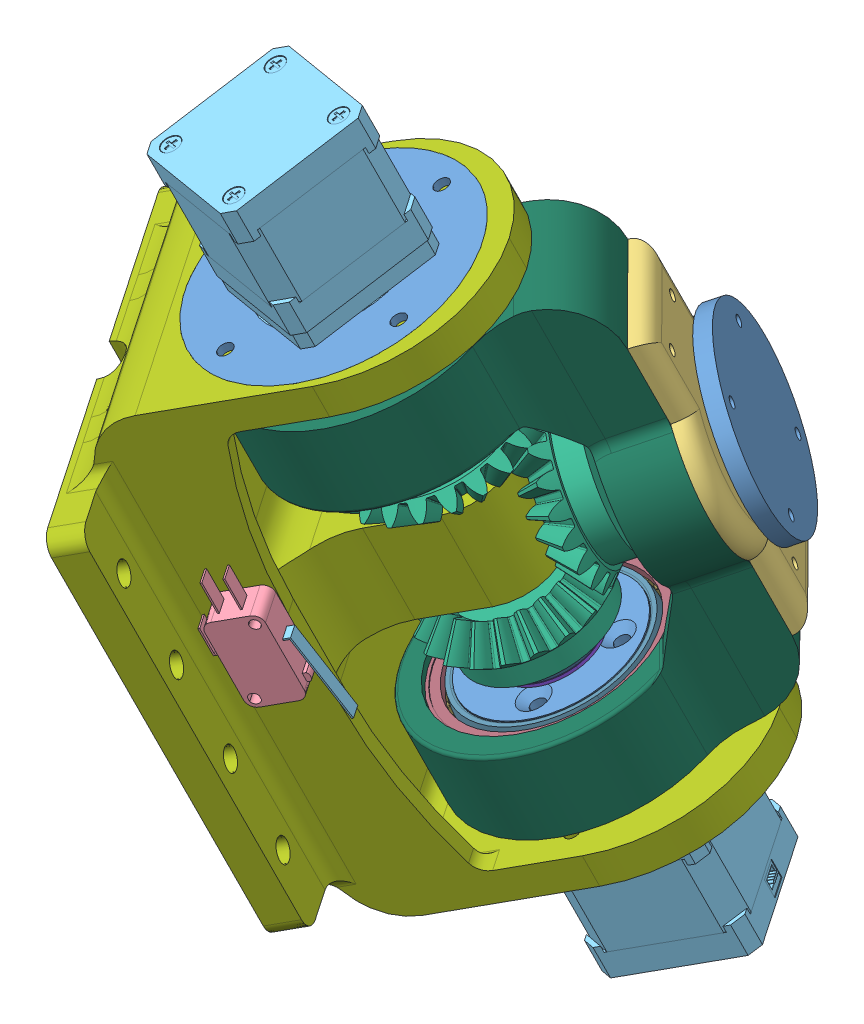
SolidWorks assembly UOM20-4A004, configuration Default. Lengths in mm.
Overall size (196.11 254.11 206.09).
236 component instances, 25 part files, 61 mates.
Components (placement in the parent):
- Motor sleeve-1: Motor sleeve [Default] at (155.4938 95.549 -26.0395) x (0.240387 -0.911388 -0.334046) z (0.948422 0.147261 0.280731) size (40 78 78)
- Motor sleeve-2: Motor sleeve [Default] at (194.9173 -53.9186 -80.823) x (-0.240387 0.911388 0.334046) z (-0.822054 -0.374149 0.429231) size (40 78 78)
- HK_1412-1: HK_1412 [Default] at (171.5998 34.486 -48.4206) x (0.240387 -0.911388 -0.334046) z (0.778305 -0.024672 0.627401) size (12 20 20)
  - HK_1412_3-1: HK_1412_3 [Default] x (1 0 0) z (0 -0.382683 0.92388) size (7.3 2 2)
  - HK_1412_3-2: HK_1412_3 [Default] x (1 0 0) z (0 -0.707107 0.707107) size (7.3 2 2)
  - HK_1412_3-3: HK_1412_3 [Default] x (1 0 0) z (0 -0.92388 0.382683) size (7.3 2 2)
  - HK_1412_3-4: HK_1412_3 [Default] x (1 0 0) z (0 -1 0) size (7.3 2 2)
  - HK_1412_3-5: HK_1412_3 [Default] x (1 0 0) z (0 -0.92388 -0.382683) size (7.3 2 2)
  - HK_1412_3-6: HK_1412_3 [Default] x (1 0 0) z (0 -0.707107 -0.707107) size (7.3 2 2)
  - HK_1412_3-7: HK_1412_3 [Default] x (1 0 0) z (0 -0.382683 -0.92388) size (7.3 2 2)
  - HK_1412_3-8: HK_1412_3 [Default] x (1 0 0) z (0 0 -1) size (7.3 2 2)
  - HK_1412_3-9: HK_1412_3 [Default] x (1 0 0) z (0 0.382683 -0.92388) size (7.3 2 2)
  - HK_1412_3-10: HK_1412_3 [Default] x (1 0 0) z (0 0.707107 -0.707107) size (7.3 2 2)
  - HK_1412_3-11: HK_1412_3 [Default] x (1 0 0) z (0 0.92388 -0.382683) size (7.3 2 2)
  - HK_1412_3-12: HK_1412_3 [Default] x (1 0 0) z (0 1 0) size (7.3 2 2)
  - HK_1412_3-13: HK_1412_3 [Default] x (1 0 0) z (0 0.92388 0.382683) size (7.3 2 2)
  - HK_1412_3-14: HK_1412_3 [Default] x (1 0 0) z (0 0.707107 0.707107) size (7.3 2 2)
  - HK_1412_3-15: HK_1412_3 [Default] x (1 0 0) z (0 0.382683 0.92388) size (7.3 2 2)
  - HK_1412_3-16: HK_1412_3 [Default] at origin size (7.3 2 2)
  - HK_1412_20-1: HK_1412_20 [Default] x (1 0 0) z (0 -0.382683 0.92388) size (7.3 2 2)
  - HK_1412_20-2: HK_1412_20 [Default] x (1 0 0) z (0 -0.707107 0.707107) size (7.3 2 2)
  - HK_1412_20-3: HK_1412_20 [Default] x (1 0 0) z (0 -0.92388 0.382683) size (7.3 2 2)
  - HK_1412_20-4: HK_1412_20 [Default] x (1 0 0) z (0 -1 0) size (7.3 2 2)
  - HK_1412_20-5: HK_1412_20 [Default] x (1 0 0) z (0 -0.92388 -0.382683) size (7.3 2 2)
  - HK_1412_20-6: HK_1412_20 [Default] x (1 0 0) z (0 -0.707107 -0.707107) size (7.3 2 2)
  - HK_1412_20-7: HK_1412_20 [Default] x (1 0 0) z (0 -0.382683 -0.92388) size (7.3 2 2)
  - HK_1412_20-8: HK_1412_20 [Default] x (1 0 0) z (0 0 -1) size (7.3 2 2)
  - HK_1412_20-9: HK_1412_20 [Default] x (1 0 0) z (0 0.382683 -0.92388) size (7.3 2 2)
  - HK_1412_20-10: HK_1412_20 [Default] x (1 0 0) z (0 0.707107 -0.707107) size (7.3 2 2)
  - HK_1412_20-11: HK_1412_20 [Default] x (1 0 0) z (0 0.92388 -0.382683) size (7.3 2 2)
  - HK_1412_20-12: HK_1412_20 [Default] x (1 0 0) z (0 1 0) size (7.3 2 2)
  - HK_1412_20-13: HK_1412_20 [Default] x (1 0 0) z (0 0.92388 0.382683) size (7.3 2 2)
  - HK_1412_20-14: HK_1412_20 [Default] x (1 0 0) z (0 0.707107 0.707107) size (7.3 2 2)
  - HK_1412_20-15: HK_1412_20 [Default] x (1 0 0) z (0 0.382683 0.92388) size (7.3 2 2)
  - HK_1412_20-16: HK_1412_20 [Default] at origin size (7.3 2 2)
  - HK_1412_37-1: HK_1412_37 [Default] at origin size (12 20 20)
- HK_1412-2: HK_1412 [Default] at (175.9267 18.081 -54.4334) x (0.240387 -0.911388 -0.334046) z (0.468046 0.410319 -0.782669) size (12 20 20)
  - HK_1412_3-1: HK_1412_3 [Default] x (1 0 0) z (0 -0.382683 0.92388) size (7.3 2 2)
  - HK_1412_3-2: HK_1412_3 [Default] x (1 0 0) z (0 -0.707107 0.707107) size (7.3 2 2)
  - HK_1412_3-3: HK_1412_3 [Default] x (1 0 0) z (0 -0.92388 0.382683) size (7.3 2 2)
  - HK_1412_3-4: HK_1412_3 [Default] x (1 0 0) z (0 -1 0) size (7.3 2 2)
  - HK_1412_3-5: HK_1412_3 [Default] x (1 0 0) z (0 -0.92388 -0.382683) size (7.3 2 2)
  - HK_1412_3-6: HK_1412_3 [Default] x (1 0 0) z (0 -0.707107 -0.707107) size (7.3 2 2)
  - HK_1412_3-7: HK_1412_3 [Default] x (1 0 0) z (0 -0.382683 -0.92388) size (7.3 2 2)
  - HK_1412_3-8: HK_1412_3 [Default] x (1 0 0) z (0 0 -1) size (7.3 2 2)
  - HK_1412_3-9: HK_1412_3 [Default] x (1 0 0) z (0 0.382683 -0.92388) size (7.3 2 2)
  - HK_1412_3-10: HK_1412_3 [Default] x (1 0 0) z (0 0.707107 -0.707107) size (7.3 2 2)
  - HK_1412_3-11: HK_1412_3 [Default] x (1 0 0) z (0 0.92388 -0.382683) size (7.3 2 2)
  - HK_1412_3-12: HK_1412_3 [Default] x (1 0 0) z (0 1 0) size (7.3 2 2)
  - HK_1412_3-13: HK_1412_3 [Default] x (1 0 0) z (0 0.92388 0.382683) size (7.3 2 2)
  - HK_1412_3-14: HK_1412_3 [Default] x (1 0 0) z (0 0.707107 0.707107) size (7.3 2 2)
  - HK_1412_3-15: HK_1412_3 [Default] x (1 0 0) z (0 0.382683 0.92388) size (7.3 2 2)
  - HK_1412_3-16: HK_1412_3 [Default] at origin size (7.3 2 2)
  - HK_1412_20-1: HK_1412_20 [Default] x (1 0 0) z (0 -0.382683 0.92388) size (7.3 2 2)
  - HK_1412_20-2: HK_1412_20 [Default] x (1 0 0) z (0 -0.707107 0.707107) size (7.3 2 2)
  - HK_1412_20-3: HK_1412_20 [Default] x (1 0 0) z (0 -0.92388 0.382683) size (7.3 2 2)
  - HK_1412_20-4: HK_1412_20 [Default] x (1 0 0) z (0 -1 0) size (7.3 2 2)
  - HK_1412_20-5: HK_1412_20 [Default] x (1 0 0) z (0 -0.92388 -0.382683) size (7.3 2 2)
  - HK_1412_20-6: HK_1412_20 [Default] x (1 0 0) z (0 -0.707107 -0.707107) size (7.3 2 2)
  - HK_1412_20-7: HK_1412_20 [Default] x (1 0 0) z (0 -0.382683 -0.92388) size (7.3 2 2)
  - HK_1412_20-8: HK_1412_20 [Default] x (1 0 0) z (0 0 -1) size (7.3 2 2)
  - HK_1412_20-9: HK_1412_20 [Default] x (1 0 0) z (0 0.382683 -0.92388) size (7.3 2 2)
  - HK_1412_20-10: HK_1412_20 [Default] x (1 0 0) z (0 0.707107 -0.707107) size (7.3 2 2)
  - HK_1412_20-11: HK_1412_20 [Default] x (1 0 0) z (0 0.92388 -0.382683) size (7.3 2 2)
  - HK_1412_20-12: HK_1412_20 [Default] x (1 0 0) z (0 1 0) size (7.3 2 2)
  - HK_1412_20-13: HK_1412_20 [Default] x (1 0 0) z (0 0.92388 0.382683) size (7.3 2 2)
  - HK_1412_20-14: HK_1412_20 [Default] x (1 0 0) z (0 0.707107 0.707107) size (7.3 2 2)
  - HK_1412_20-15: HK_1412_20 [Default] x (1 0 0) z (0 0.382683 0.92388) size (7.3 2 2)
  - HK_1412_20-16: HK_1412_20 [Default] at origin size (7.3 2 2)
  - HK_1412_37-1: HK_1412_37 [Default] at origin size (12 20 20)
- 17HS15-1684D-HG10-AR3-2: 17HS15-1684D-HG10-AR3 [Default] at (196.1193 -58.4755 -82.4933) x (0.822054 0.374149 -0.429231) z (-0.240387 0.911388 0.334046) size (42.88 42 103.5)
- 17HS15-1684D-HG10-AR3-3: 17HS15-1684D-HG10-AR3 [Default] at (154.2919 100.1059 -24.3693) x (-0.948422 -0.147261 -0.280731) z (0.240387 -0.911388 -0.334046) size (42.88 42 103.5)
- shaft-1: shaft [Default] at (185.6624 -18.8302 -67.9623) x (-0.240387 0.911388 0.334046) z (-0.716686 0.065452 -0.694318) size (42 17 17)
- shaft-2: shaft [Default] at (164.7487 60.4605 -38.9003) x (0.240387 -0.911388 -0.334046) z (-0.880225 -0.059609 -0.470799) size (42 17 17)
- AXK_1528___AS_1528___AS_1528-2: AXK_1528___AS_1528___AS_1528 [Default] at (165.5901 57.2707 -40.0694) x (0.240387 -0.911388 -0.334046) z (0.891346 0.343519 -0.295799) size (4 28 28)
  - AXK_1528___AS_1528___AS_1528_3-1: AXK_1528___AS_1528___AS_1528_3 [Default] x (1 0 0) z (0 -0.309017 0.951057) size (2 5 2)
  - AXK_1528___AS_1528___AS_1528_3-2: AXK_1528___AS_1528___AS_1528_3 [Default] x (1 0 0) z (0 -0.587785 0.809017) size (2 5 2)
  - AXK_1528___AS_1528___AS_1528_3-3: AXK_1528___AS_1528___AS_1528_3 [Default] x (1 0 0) z (0 -0.809017 0.587785) size (2 5 2)
  - AXK_1528___AS_1528___AS_1528_3-4: AXK_1528___AS_1528___AS_1528_3 [Default] x (1 0 0) z (0 -0.951057 0.309017) size (2 5 2)
  - AXK_1528___AS_1528___AS_1528_3-5: AXK_1528___AS_1528___AS_1528_3 [Default] x (1 0 0) z (0 -1 0) size (2 5 2)
  - AXK_1528___AS_1528___AS_1528_3-6: AXK_1528___AS_1528___AS_1528_3 [Default] x (1 0 0) z (0 -0.951057 -0.309017) size (2 5 2)
  - AXK_1528___AS_1528___AS_1528_3-7: AXK_1528___AS_1528___AS_1528_3 [Default] x (1 0 0) z (0 -0.809017 -0.587785) size (2 5 2)
  - AXK_1528___AS_1528___AS_1528_3-8: AXK_1528___AS_1528___AS_1528_3 [Default] x (1 0 0) z (0 -0.587785 -0.809017) size (2 5 2)
  - AXK_1528___AS_1528___AS_1528_3-9: AXK_1528___AS_1528___AS_1528_3 [Default] x (1 0 0) z (0 -0.309017 -0.951057) size (2 5 2)
  - AXK_1528___AS_1528___AS_1528_3-10: AXK_1528___AS_1528___AS_1528_3 [Default] x (1 0 0) z (0 0 -1) size (2 5 2)
  - AXK_1528___AS_1528___AS_1528_3-11: AXK_1528___AS_1528___AS_1528_3 [Default] x (1 0 0) z (0 0.309017 -0.951057) size (2 5 2)
  - AXK_1528___AS_1528___AS_1528_3-12: AXK_1528___AS_1528___AS_1528_3 [Default] x (1 0 0) z (0 0.587785 -0.809017) size (2 5 2)
  - AXK_1528___AS_1528___AS_1528_3-13: AXK_1528___AS_1528___AS_1528_3 [Default] x (1 0 0) z (0 0.809017 -0.587785) size (2 5 2)
  - AXK_1528___AS_1528___AS_1528_3-14: AXK_1528___AS_1528___AS_1528_3 [Default] x (1 0 0) z (0 0.951057 -0.309017) size (2 5 2)
  - AXK_1528___AS_1528___AS_1528_3-15: AXK_1528___AS_1528___AS_1528_3 [Default] x (1 0 0) z (0 1 0) size (2 5 2)
  - AXK_1528___AS_1528___AS_1528_3-16: AXK_1528___AS_1528___AS_1528_3 [Default] x (1 0 0) z (0 0.951057 0.309017) size (2 5 2)
  - AXK_1528___AS_1528___AS_1528_3-17: AXK_1528___AS_1528___AS_1528_3 [Default] x (1 0 0) z (0 0.809017 0.587785) size (2 5 2)
  - AXK_1528___AS_1528___AS_1528_3-18: AXK_1528___AS_1528___AS_1528_3 [Default] x (1 0 0) z (0 0.587785 0.809017) size (2 5 2)
  - AXK_1528___AS_1528___AS_1528_3-19: AXK_1528___AS_1528___AS_1528_3 [Default] x (1 0 0) z (0 0.309017 0.951057) size (2 5 2)
  - AXK_1528___AS_1528___AS_1528_3-20: AXK_1528___AS_1528___AS_1528_3 [Default] at origin size (2 5 2)
  - AXK_1528___AS_1528___AS_1528_24-1: AXK_1528___AS_1528___AS_1528_24 [Default] at origin size (1 28 28)
  - AXK_1528___AS_1528___AS_1528_26-1: AXK_1528___AS_1528___AS_1528_26 [Default] at origin size (1 28 28)
  - AXK_1528___AS_1528___AS_1528_28-1: AXK_1528___AS_1528___AS_1528_28 [Default] at origin size (1.6 28 28)
- 2mm spacer-1: 2mm spacer [Default] at (166.792 52.7138 -41.7397) x (0.953181 0.156591 0.258701) z (-0.240387 0.911388 0.334046) size (28 28 1.5)
- AXK_1528___AS_1528___AS_1528-3: AXK_1528___AS_1528___AS_1528 [Default] at (184.8211 -15.6403 -66.7931) x (0.240387 -0.911388 -0.334046) z (0.94161 0.135359 0.3083) size (4 28 28)
  - AXK_1528___AS_1528___AS_1528_3-1: AXK_1528___AS_1528___AS_1528_3 [Default] x (1 0 0) z (0 -0.309017 0.951057) size (2 5 2)
  - AXK_1528___AS_1528___AS_1528_3-2: AXK_1528___AS_1528___AS_1528_3 [Default] x (1 0 0) z (0 -0.587785 0.809017) size (2 5 2)
  - AXK_1528___AS_1528___AS_1528_3-3: AXK_1528___AS_1528___AS_1528_3 [Default] x (1 0 0) z (0 -0.809017 0.587785) size (2 5 2)
  - AXK_1528___AS_1528___AS_1528_3-4: AXK_1528___AS_1528___AS_1528_3 [Default] x (1 0 0) z (0 -0.951057 0.309017) size (2 5 2)
  - AXK_1528___AS_1528___AS_1528_3-5: AXK_1528___AS_1528___AS_1528_3 [Default] x (1 0 0) z (0 -1 0) size (2 5 2)
  - AXK_1528___AS_1528___AS_1528_3-6: AXK_1528___AS_1528___AS_1528_3 [Default] x (1 0 0) z (0 -0.951057 -0.309017) size (2 5 2)
  - AXK_1528___AS_1528___AS_1528_3-7: AXK_1528___AS_1528___AS_1528_3 [Default] x (1 0 0) z (0 -0.809017 -0.587785) size (2 5 2)
  - AXK_1528___AS_1528___AS_1528_3-8: AXK_1528___AS_1528___AS_1528_3 [Default] x (1 0 0) z (0 -0.587785 -0.809017) size (2 5 2)
  - AXK_1528___AS_1528___AS_1528_3-9: AXK_1528___AS_1528___AS_1528_3 [Default] x (1 0 0) z (0 -0.309017 -0.951057) size (2 5 2)
  - AXK_1528___AS_1528___AS_1528_3-10: AXK_1528___AS_1528___AS_1528_3 [Default] x (1 0 0) z (0 0 -1) size (2 5 2)
  - AXK_1528___AS_1528___AS_1528_3-11: AXK_1528___AS_1528___AS_1528_3 [Default] x (1 0 0) z (0 0.309017 -0.951057) size (2 5 2)
  - AXK_1528___AS_1528___AS_1528_3-12: AXK_1528___AS_1528___AS_1528_3 [Default] x (1 0 0) z (0 0.587785 -0.809017) size (2 5 2)
  - AXK_1528___AS_1528___AS_1528_3-13: AXK_1528___AS_1528___AS_1528_3 [Default] x (1 0 0) z (0 0.809017 -0.587785) size (2 5 2)
  - AXK_1528___AS_1528___AS_1528_3-14: AXK_1528___AS_1528___AS_1528_3 [Default] x (1 0 0) z (0 0.951057 -0.309017) size (2 5 2)
  - AXK_1528___AS_1528___AS_1528_3-15: AXK_1528___AS_1528___AS_1528_3 [Default] x (1 0 0) z (0 1 0) size (2 5 2)
  - AXK_1528___AS_1528___AS_1528_3-16: AXK_1528___AS_1528___AS_1528_3 [Default] x (1 0 0) z (0 0.951057 0.309017) size (2 5 2)
  - AXK_1528___AS_1528___AS_1528_3-17: AXK_1528___AS_1528___AS_1528_3 [Default] x (1 0 0) z (0 0.809017 0.587785) size (2 5 2)
  - AXK_1528___AS_1528___AS_1528_3-18: AXK_1528___AS_1528___AS_1528_3 [Default] x (1 0 0) z (0 0.587785 0.809017) size (2 5 2)
  - AXK_1528___AS_1528___AS_1528_3-19: AXK_1528___AS_1528___AS_1528_3 [Default] x (1 0 0) z (0 0.309017 0.951057) size (2 5 2)
  - AXK_1528___AS_1528___AS_1528_3-20: AXK_1528___AS_1528___AS_1528_3 [Default] at origin size (2 5 2)
  - AXK_1528___AS_1528___AS_1528_24-1: AXK_1528___AS_1528___AS_1528_24 [Default] at origin size (1 28 28)
  - AXK_1528___AS_1528___AS_1528_26-1: AXK_1528___AS_1528___AS_1528_26 [Default] at origin size (1 28 28)
  - AXK_1528___AS_1528___AS_1528_28-1: AXK_1528___AS_1528___AS_1528_28 [Default] at origin size (1.6 28 28)
- 2mm spacer-2: 2mm spacer [Default] at (183.9797 -12.4505 -65.6239) x (0.94161 0.135359 0.3083) z (-0.240387 0.911388 0.334046) size (28 28 1.5)
- NKI_50_25-1: NKI_50_25 [Default] at (185.3018 -17.4631 -67.4612) x (0.240387 -0.911388 -0.334046) z (0.92532 0.11119 0.36252) size (25 68.42 68)
  - NKI_50_25_37-1: NKI_50_25_37 [Default] x (1 0 0) z (0 -0.189251 0.981929) size (18.8 3.5 3.5)
  - NKI_50_25_37-2: NKI_50_25_37 [Default] x (1 0 0) z (0 -0.371662 0.928368) size (18.8 3.5 3.5)
  - NKI_50_25_37-3: NKI_50_25_37 [Default] x (1 0 0) z (0 -0.540641 0.841254) size (18.8 3.5 3.5)
  - NKI_50_25_37-4: NKI_50_25_37 [Default] x (1 0 0) z (0 -0.690079 0.723734) size (18.8 3.5 3.5)
  - NKI_50_25_37-5: NKI_50_25_37 [Default] x (1 0 0) z (0 -0.814576 0.580057) size (18.8 3.5 3.5)
  - NKI_50_25_37-6: NKI_50_25_37 [Default] x (1 0 0) z (0 -0.909632 0.415415) size (18.8 3.5 3.5)
  - NKI_50_25_37-7: NKI_50_25_37 [Default] x (1 0 0) z (0 -0.971812 0.235759) size (18.8 3.5 3.5)
  - NKI_50_25_37-8: NKI_50_25_37 [Default] x (1 0 0) z (0 -0.998867 0.047582) size (18.8 3.5 3.5)
  - NKI_50_25_37-9: NKI_50_25_37 [Default] x (1 0 0) z (0 -0.989821 -0.142315) size (18.8 3.5 3.5)
  - NKI_50_25_37-10: NKI_50_25_37 [Default] x (1 0 0) z (0 -0.945001 -0.327068) size (18.8 3.5 3.5)
  - NKI_50_25_37-11: NKI_50_25_37 [Default] x (1 0 0) z (0 -0.866025 -0.5) size (18.8 3.5 3.5)
  - NKI_50_25_37-12: NKI_50_25_37 [Default] x (1 0 0) z (0 -0.75575 -0.654861) size (18.8 3.5 3.5)
  - NKI_50_25_37-13: NKI_50_25_37 [Default] x (1 0 0) z (0 -0.618159 -0.786053) size (18.8 3.5 3.5)
  - NKI_50_25_37-14: NKI_50_25_37 [Default] x (1 0 0) z (0 -0.458227 -0.888835) size (18.8 3.5 3.5)
  - NKI_50_25_37-15: NKI_50_25_37 [Default] x (1 0 0) z (0 -0.281733 -0.959493) size (18.8 3.5 3.5)
  - NKI_50_25_37-16: NKI_50_25_37 [Default] x (1 0 0) z (0 -0.095056 -0.995472) size (18.8 3.5 3.5)
  - NKI_50_25_37-17: NKI_50_25_37 [Default] x (1 0 0) z (0 0.095056 -0.995472) size (18.8 3.5 3.5)
  - NKI_50_25_37-18: NKI_50_25_37 [Default] x (1 0 0) z (0 0.281733 -0.959493) size (18.8 3.5 3.5)
  - NKI_50_25_37-19: NKI_50_25_37 [Default] x (1 0 0) z (0 0.458227 -0.888835) size (18.8 3.5 3.5)
  - NKI_50_25_37-20: NKI_50_25_37 [Default] x (1 0 0) z (0 0.618159 -0.786053) size (18.8 3.5 3.5)
  - NKI_50_25_37-21: NKI_50_25_37 [Default] x (1 0 0) z (0 0.75575 -0.654861) size (18.8 3.5 3.5)
  - NKI_50_25_37-22: NKI_50_25_37 [Default] x (1 0 0) z (0 0.866025 -0.5) size (18.8 3.5 3.5)
  - NKI_50_25_37-23: NKI_50_25_37 [Default] x (1 0 0) z (0 0.945001 -0.327068) size (18.8 3.5 3.5)
  - NKI_50_25_37-24: NKI_50_25_37 [Default] x (1 0 0) z (0 0.989821 -0.142315) size (18.8 3.5 3.5)
  - NKI_50_25_37-25: NKI_50_25_37 [Default] x (1 0 0) z (0 0.998867 0.047582) size (18.8 3.5 3.5)
  - NKI_50_25_37-26: NKI_50_25_37 [Default] x (1 0 0) z (0 0.971812 0.235759) size (18.8 3.5 3.5)
  - NKI_50_25_37-27: NKI_50_25_37 [Default] x (1 0 0) z (0 0.909632 0.415415) size (18.8 3.5 3.5)
  - NKI_50_25_37-28: NKI_50_25_37 [Default] x (1 0 0) z (0 0.814576 0.580057) size (18.8 3.5 3.5)
  - NKI_50_25_37-29: NKI_50_25_37 [Default] x (1 0 0) z (0 0.690079 0.723734) size (18.8 3.5 3.5)
  - NKI_50_25_37-30: NKI_50_25_37 [Default] x (1 0 0) z (0 0.540641 0.841254) size (18.8 3.5 3.5)
  - NKI_50_25_37-31: NKI_50_25_37 [Default] x (1 0 0) z (0 0.371662 0.928368) size (18.8 3.5 3.5)
  - NKI_50_25_37-32: NKI_50_25_37 [Default] x (1 0 0) z (0 0.189251 0.981929) size (18.8 3.5 3.5)
  - NKI_50_25_37-33: NKI_50_25_37 [Default] at origin size (18.8 3.5 3.5)
  - NKI_50_25_71-1: NKI_50_25_71 [Default] at origin size (25 68.42 68)
  - NKI_50_25_73-1: NKI_50_25_73 [Default] at origin size (25 55 55)
- NKI_50_25-2: NKI_50_25 [Default] at (159.0996 81.8782 -31.0502) x (0.240387 -0.911388 -0.334046) z (0.894286 0.074124 0.441314) size (25 68.42 68)
  - NKI_50_25_37-1: NKI_50_25_37 [Default] x (1 0 0) z (0 -0.189251 0.981929) size (18.8 3.5 3.5)
  - NKI_50_25_37-2: NKI_50_25_37 [Default] x (1 0 0) z (0 -0.371662 0.928368) size (18.8 3.5 3.5)
  - NKI_50_25_37-3: NKI_50_25_37 [Default] x (1 0 0) z (0 -0.540641 0.841254) size (18.8 3.5 3.5)
  - NKI_50_25_37-4: NKI_50_25_37 [Default] x (1 0 0) z (0 -0.690079 0.723734) size (18.8 3.5 3.5)
  - NKI_50_25_37-5: NKI_50_25_37 [Default] x (1 0 0) z (0 -0.814576 0.580057) size (18.8 3.5 3.5)
  - NKI_50_25_37-6: NKI_50_25_37 [Default] x (1 0 0) z (0 -0.909632 0.415415) size (18.8 3.5 3.5)
  - NKI_50_25_37-7: NKI_50_25_37 [Default] x (1 0 0) z (0 -0.971812 0.235759) size (18.8 3.5 3.5)
  - NKI_50_25_37-8: NKI_50_25_37 [Default] x (1 0 0) z (0 -0.998867 0.047582) size (18.8 3.5 3.5)
  - NKI_50_25_37-9: NKI_50_25_37 [Default] x (1 0 0) z (0 -0.989821 -0.142315) size (18.8 3.5 3.5)
  - NKI_50_25_37-10: NKI_50_25_37 [Default] x (1 0 0) z (0 -0.945001 -0.327068) size (18.8 3.5 3.5)
  - NKI_50_25_37-11: NKI_50_25_37 [Default] x (1 0 0) z (0 -0.866025 -0.5) size (18.8 3.5 3.5)
  - NKI_50_25_37-12: NKI_50_25_37 [Default] x (1 0 0) z (0 -0.75575 -0.654861) size (18.8 3.5 3.5)
  - NKI_50_25_37-13: NKI_50_25_37 [Default] x (1 0 0) z (0 -0.618159 -0.786053) size (18.8 3.5 3.5)
  - NKI_50_25_37-14: NKI_50_25_37 [Default] x (1 0 0) z (0 -0.458227 -0.888835) size (18.8 3.5 3.5)
  - NKI_50_25_37-15: NKI_50_25_37 [Default] x (1 0 0) z (0 -0.281733 -0.959493) size (18.8 3.5 3.5)
  - NKI_50_25_37-16: NKI_50_25_37 [Default] x (1 0 0) z (0 -0.095056 -0.995472) size (18.8 3.5 3.5)
  - NKI_50_25_37-17: NKI_50_25_37 [Default] x (1 0 0) z (0 0.095056 -0.995472) size (18.8 3.5 3.5)
  - NKI_50_25_37-18: NKI_50_25_37 [Default] x (1 0 0) z (0 0.281733 -0.959493) size (18.8 3.5 3.5)
  - NKI_50_25_37-19: NKI_50_25_37 [Default] x (1 0 0) z (0 0.458227 -0.888835) size (18.8 3.5 3.5)
  - NKI_50_25_37-20: NKI_50_25_37 [Default] x (1 0 0) z (0 0.618159 -0.786053) size (18.8 3.5 3.5)
  - NKI_50_25_37-21: NKI_50_25_37 [Default] x (1 0 0) z (0 0.75575 -0.654861) size (18.8 3.5 3.5)
  - NKI_50_25_37-22: NKI_50_25_37 [Default] x (1 0 0) z (0 0.866025 -0.5) size (18.8 3.5 3.5)
  - NKI_50_25_37-23: NKI_50_25_37 [Default] x (1 0 0) z (0 0.945001 -0.327068) size (18.8 3.5 3.5)
  - NKI_50_25_37-24: NKI_50_25_37 [Default] x (1 0 0) z (0 0.989821 -0.142315) size (18.8 3.5 3.5)
  - NKI_50_25_37-25: NKI_50_25_37 [Default] x (1 0 0) z (0 0.998867 0.047582) size (18.8 3.5 3.5)
  - NKI_50_25_37-26: NKI_50_25_37 [Default] x (1 0 0) z (0 0.971812 0.235759) size (18.8 3.5 3.5)
  - NKI_50_25_37-27: NKI_50_25_37 [Default] x (1 0 0) z (0 0.909632 0.415415) size (18.8 3.5 3.5)
  - NKI_50_25_37-28: NKI_50_25_37 [Default] x (1 0 0) z (0 0.814576 0.580057) size (18.8 3.5 3.5)
  - NKI_50_25_37-29: NKI_50_25_37 [Default] x (1 0 0) z (0 0.690079 0.723734) size (18.8 3.5 3.5)
  - NKI_50_25_37-30: NKI_50_25_37 [Default] x (1 0 0) z (0 0.540641 0.841254) size (18.8 3.5 3.5)
  - NKI_50_25_37-31: NKI_50_25_37 [Default] x (1 0 0) z (0 0.371662 0.928368) size (18.8 3.5 3.5)
  - NKI_50_25_37-32: NKI_50_25_37 [Default] x (1 0 0) z (0 0.189251 0.981929) size (18.8 3.5 3.5)
  - NKI_50_25_37-33: NKI_50_25_37 [Default] at origin size (18.8 3.5 3.5)
  - NKI_50_25_71-1: NKI_50_25_71 [Default] at origin size (25 68.42 68)
  - NKI_50_25_73-1: NKI_50_25_73 [Default] at origin size (25 55 55)
- Wrist output frame-1: Wrist output frame [Default] at (159.0996 81.8782 -31.0502) x (0.240387 -0.911388 -0.334046) z (0.703072 -0.073793 0.70728) size (134 102 78)
- 7203_BEY-3: 7203_BEY [Default] at (209.3376 41.464 -85.2059) x (-0.669256 -0.404879 0.623032) z (0.360262 -0.910164 -0.204482) size (12 40 40)
  - 7203_BEY_3-1: 7203_BEY_3 [Default] x (1 0 0) z (0 -0.587785 0.809017) size (7.14 7.14 7.14)
  - 7203_BEY_3-2: 7203_BEY_3 [Default] x (1 0 0) z (0 -0.951057 0.309017) size (7.14 7.14 7.14)
  - 7203_BEY_3-3: 7203_BEY_3 [Default] x (1 0 0) z (0 -0.951057 -0.309017) size (7.14 7.14 7.14)
  - 7203_BEY_3-4: 7203_BEY_3 [Default] x (1 0 0) z (0 -0.587785 -0.809017) size (7.14 7.14 7.14)
  - 7203_BEY_3-5: 7203_BEY_3 [Default] x (1 0 0) z (0 0 -1) size (7.14 7.14 7.14)
  - 7203_BEY_3-6: 7203_BEY_3 [Default] x (1 0 0) z (0 0.587785 -0.809017) size (7.14 7.14 7.14)
  - 7203_BEY_3-7: 7203_BEY_3 [Default] x (1 0 0) z (0 0.951057 -0.309017) size (7.14 7.14 7.14)
  - 7203_BEY_3-8: 7203_BEY_3 [Default] x (1 0 0) z (0 0.951057 0.309017) size (7.14 7.14 7.14)
  - 7203_BEY_3-9: 7203_BEY_3 [Default] x (1 0 0) z (0 0.587785 0.809017) size (7.14 7.14 7.14)
  - 7203_BEY_3-10: 7203_BEY_3 [Default] at origin size (7.14 7.14 7.14)
  - 7203_BEY_14-1: 7203_BEY_14 [Default] at origin size (12 40 40)
  - 7203_BEY_16-1: 7203_BEY_16 [Default] at origin size (12 26.25 26.25)
- 7203_BEY-4: 7203_BEY [Default] at (209.3376 41.464 -85.2059) x (0.669256 0.404879 -0.623032) z (0.392603 0.519205 0.759138) size (12 40 40)
  - 7203_BEY_3-1: 7203_BEY_3 [Default] x (1 0 0) z (0 -0.587785 0.809017) size (7.14 7.14 7.14)
  - 7203_BEY_3-2: 7203_BEY_3 [Default] x (1 0 0) z (0 -0.951057 0.309017) size (7.14 7.14 7.14)
  - 7203_BEY_3-3: 7203_BEY_3 [Default] x (1 0 0) z (0 -0.951057 -0.309017) size (7.14 7.14 7.14)
  - 7203_BEY_3-4: 7203_BEY_3 [Default] x (1 0 0) z (0 -0.587785 -0.809017) size (7.14 7.14 7.14)
  - 7203_BEY_3-5: 7203_BEY_3 [Default] x (1 0 0) z (0 0 -1) size (7.14 7.14 7.14)
  - 7203_BEY_3-6: 7203_BEY_3 [Default] x (1 0 0) z (0 0.587785 -0.809017) size (7.14 7.14 7.14)
  - 7203_BEY_3-7: 7203_BEY_3 [Default] x (1 0 0) z (0 0.951057 -0.309017) size (7.14 7.14 7.14)
  - 7203_BEY_3-8: 7203_BEY_3 [Default] x (1 0 0) z (0 0.951057 0.309017) size (7.14 7.14 7.14)
  - 7203_BEY_3-9: 7203_BEY_3 [Default] x (1 0 0) z (0 0.587785 0.809017) size (7.14 7.14 7.14)
  - 7203_BEY_3-10: 7203_BEY_3 [Default] at origin size (7.14 7.14 7.14)
  - 7203_BEY_14-1: 7203_BEY_14 [Default] at origin size (12 40 40)
  - 7203_BEY_16-1: 7203_BEY_16 [Default] at origin size (12 26.25 26.25)
- Output shaft-1: Output shaft [Default] at (187.8485 28.6374 -65.1828) x (-0.253722 -0.663574 -0.703772) z (0.669256 0.404879 -0.623032) size (60 60 52.05)
- 4mm spacer-1: 4mm spacer [Default] at (198.59 35.1357 -75.1825) x (-0.173248 -0.730359 -0.660728) z (0.669256 0.404879 -0.623032) size (26 26 4)
- Wrist output cap-1: Wrist output cap [Default] at (217.3687 46.3226 -92.6823) x (0.240387 -0.911388 -0.334046) z (0.669256 0.404879 -0.623032) size (94 60 6.33)
- V_152_1C25-1: V_152_1C25 [Default] at (117.4398 35.9388 -69.805) x (-0.240387 0.911388 0.334046) z (-0.516179 0.171422 -0.839151) size (48.18 24.9 10.3)
  - V_152_1C25_BASE-1: V_152_1C25_BASE [Default] at origin size (37.8 20.43 10.3)
  - V_152_1C25_ACTUATOR-1: V_152_1C25_ACTUATOR [Default] at (-8.6 2.8 -0.2) size (27.28 6.1 4.3)
- V_152_1C25-2: V_152_1C25 [Default] at (165.0831 20.1165 7.6486) x (-0.240387 0.911388 0.334046) z (-0.516179 0.171422 -0.839151) size (48.18 24.9 10.3)
  - V_152_1C25_BASE-1: V_152_1C25_BASE [Default] at origin size (37.8 20.43 10.3)
  - V_152_1C25_ACTUATOR-1: V_152_1C25_ACTUATOR [Default] at (-8.6 2.8 -0.2) size (27.28 6.1 4.3)
- straight miter gear_am-1: straight miter gear_am [A 1C 4MYKW25020] at (181.8465 -4.3627 -62.6596) x (-0.240387 0.911388 0.334046) z (0.716686 -0.065452 0.694318) size (19.66 53.34 53.34)
- straight miter gear_am-2: straight miter gear_am [A 1C 4MYKW25020] at (168.5646 45.9931 -44.2029) x (0.240387 -0.911388 -0.334046) z (0.880225 0.059609 0.470799) size (19.66 53.34 53.34)
- straight miter gear_am-3: straight miter gear_am [A 1C 4MYKW25020] at (193.6549 32.1501 -70.5882) x (-0.669256 -0.404879 0.623032) z (-0.253722 -0.663574 -0.703772) size (19.66 53.34 53.34)
- Wrist input frame_attachment-1: Wrist input frame_attachment [Default] at (81.709 -99.7079 -154.6199) x (-0.822054 -0.374149 0.429231) z (-0.240387 0.911388 0.334046) size (114 122 164)
Mates (geometry in assembly coordinates):
- Concentric10: concentric aligned: cylinder of Motor sleeve-2 through (210.327 -112.3416 -102.2365) axis (0.240387 -0.911388 -0.334046) radius 21; cylinder of 17HS15-1684D-HG10-AR3-2 through (186.5038 -22.02 -69.1314) axis (0.240387 -0.911388 -0.334046) radius 21
- Concentric11: concentric aligned: cylinder of Motor sleeve-2 through (176.2687 -14.4632 -82.1463) axis (-0.240387 0.911388 0.334046) radius 2.25; cylinder of 17HS15-1684D-HG10-AR3-2 through (177.4706 -19.0201 -83.8166) axis (-0.240387 0.911388 0.334046) radius 2.25
- Concentric13: concentric aligned: cylinder of Motor sleeve-1 through (140.0842 153.972 -4.626) axis (-0.240387 0.911388 0.334046) radius 21; cylinder of 17HS15-1684D-HG10-AR3-3 through (163.9074 63.6504 -37.7311) axis (-0.240387 0.911388 0.334046) radius 21
- Concentric16: concentric aligned: cylinder of Motor sleeve-1 through (168.7259 65.8187 -55.1475) axis (0.240387 -0.911388 -0.334046) radius 2.25; circle of 17HS15-1684D-HG10-AR3-3
- Coincident5: coincident anti-aligned: plane of Motor sleeve-2 through (175.664 -18.4202 -86.7536) normal (0.240387 -0.911388 -0.334046); plane of 17HS15-1684D-HG10-AR3-2 through (186.5038 -22.02 -69.1314) normal (-0.240387 0.911388 0.334046)
- Coincident7: coincident anti-aligned: plane of Motor sleeve-1 through (168.2473 71.7207 -56.6265) normal (-0.240387 0.911388 0.334046); plane of 17HS15-1684D-HG10-AR3-3 through (163.9074 63.6504 -37.7311) normal (0.240387 -0.911388 -0.334046)
- Concentric17: concentric aligned: cylinder of 17HS15-1684D-HG10-AR3-2 through (184.7489 -15.3669 -66.6929) axis (0.240387 -0.911388 -0.334046) radius 4; cylinder of shaft-1 through (175.5661 19.4481 -53.9323) axis (0.240387 -0.911388 -0.334046) radius 4
- Distance2: distance = 1.5 mm anti-aligned: plane of 17HS15-1684D-HG10-AR3-2 through (186.023 -20.1972 -68.4633) normal (-0.240387 0.911388 0.334046); plane of shaft-1 through (185.6624 -18.8302 -67.9623) normal (0.240387 -0.911388 -0.334046)
- Concentric18: concentric aligned: cylinder of 17HS15-1684D-HG10-AR3-3 through (165.6622 56.9973 -40.1696) axis (-0.240387 0.911388 0.334046) radius 4; cylinder of shaft-2 through (174.845 22.1823 -52.9302) axis (-0.240387 0.911388 0.334046) radius 4
- Distance3: distance = 1.5 mm anti-aligned: plane of 17HS15-1684D-HG10-AR3-3 through (164.3881 61.8276 -38.3992) normal (0.240387 -0.911388 -0.334046); plane of shaft-2 through (164.7487 60.4605 -38.9003) normal (-0.240387 0.911388 0.334046)
- Concentric20: concentric anti-aligned: cylinder of shaft-2 through (165.9506 55.9036 -40.5705) axis (-0.240387 0.911388 0.334046) radius 7.5; circle of AXK_1528___AS_1528___AS_1528-2/AXK_1528___AS_1528___AS_1528_24-1
- Coincident10: coincident anti-aligned: plane of Motor sleeve-1 through (166.8659 62.36 -47.0495) normal (0.240387 -0.911388 -0.334046); plane of AXK_1528___AS_1528___AS_1528-2/AXK_1528___AS_1528___AS_1528_26-1 through (159.7286 62.2665 -51.9305) normal (-0.240387 0.911388 0.334046)
- Concentric21: concentric anti-aligned: cylinder of shaft-2 through (174.845 22.1823 -52.9302) axis (-0.240387 0.911388 0.334046) radius 7.5; cylinder of 2mm spacer-1 through (166.4314 54.0808 -41.2386) axis (0.240387 -0.911388 -0.334046) radius 7.5
- Coincident11: coincident anti-aligned: plane of shaft-2 through (166.4314 54.0808 -41.2386) normal (0.240387 -0.911388 -0.334046); plane of 2mm spacer-1 through (166.4314 54.0808 -41.2386) normal (-0.240387 0.911388 0.334046)
- Concentric23: concentric anti-aligned: cylinder of shaft-1 through (184.4605 -14.2732 -66.292) axis (0.240387 -0.911388 -0.334046) radius 7.5; cylinder of AXK_1528___AS_1528___AS_1528-3/AXK_1528___AS_1528___AS_1528_28-1 through (185.0134 -16.3694 -67.0603) axis (-0.240387 0.911388 0.334046) radius 7.5
- Coincident14: coincident anti-aligned: plane of Motor sleeve-2 through (180.9143 -16.006 -74.594) normal (-0.240387 0.911388 0.334046); plane of AXK_1528___AS_1528___AS_1528-3/AXK_1528___AS_1528___AS_1528_24-1 through (187.0701 -14.5482 -74.1415) normal (0.240387 -0.911388 -0.334046)
- Concentric241: concentric aligned: cylinder of shaft-1 through (175.5661 19.4481 -53.9323) axis (0.240387 -0.911388 -0.334046) radius 7.5; cylinder of 2mm spacer-2 through (183.6191 -11.0834 -65.1229) axis (0.240387 -0.911388 -0.334046) radius 14
- Coincident15: coincident anti-aligned: plane of shaft-1 through (183.9797 -12.4505 -65.6239) normal (-0.240387 0.911388 0.334046); plane of 2mm spacer-2 through (183.9797 -12.4505 -65.6239) normal (0.240387 -0.911388 -0.334046)
- Concentric248: concentric aligned: cylinder of Motor sleeve-2 through (210.327 -112.3416 -102.2365) axis (0.240387 -0.911388 -0.334046) radius 25; cylinder of NKI_50_25-1/NKI_50_25_73-1 through (191.3115 -40.2478 -75.8123) axis (0.240387 -0.911388 -0.334046) radius 25
- Distance4: distance = 0 mm anti-aligned: plane of Motor sleeve-2 through (178.407 -35.9622 -96.7911) normal (-0.240387 0.911388 0.334046); plane of NKI_50_25-1/NKI_50_25_73-1 through (198.8188 -30.1039 -98.0857) normal (0.240387 -0.911388 -0.334046)
- Concentric249: concentric anti-aligned: cylinder of Motor sleeve-1 through (140.0842 153.972 -4.626) axis (-0.240387 0.911388 0.334046) radius 25; cylinder of NKI_50_25-2/NKI_50_25_73-1 through (165.1093 59.0935 -39.4013) axis (0.240387 -0.911388 -0.334046) radius 25
- Distance5: distance = 0 mm anti-aligned: plane of Motor sleeve-1 through (164.2662 91.4857 -53.5447) normal (0.240387 -0.911388 -0.334046); plane of NKI_50_25-2/NKI_50_25_73-1 through (169.2529 92.7678 -53.4541) normal (-0.240387 0.911388 0.334046)
- Concentric250: concentric anti-aligned: cylinder of NKI_50_25-2/NKI_50_25_71-1 through (171.119 36.3088 -47.7525) axis (0.240387 -0.911388 -0.334046) radius 34; cylinder of Wrist output frame-1 through (165.1093 59.0935 -39.4013) axis (-0.240387 0.911388 0.334046) radius 34
- Distance6: distance = 0 mm anti-aligned: plane of Wrist output frame-1 through (185.3018 -17.4631 -67.4612) normal (0.240387 -0.911388 -0.334046); plane of NKI_50_25-1/NKI_50_25_71-1 through (195.0965 -4.2285 -96.521) normal (-0.240387 0.911388 0.334046)
- Concentric254: concentric aligned: cylinder of Wrist output frame-1 through (214.6923 44.7035 -90.1908) axis (-0.669256 -0.404879 0.623032) radius 20; cylinder of 7203_BEY-3/7203_BEY_16-1 through (201.3066 36.6055 -77.7295) axis (-0.669256 -0.404879 0.623032) radius 8.5
- Distance9: distance = 0 mm aligned: plane of 7203_BEY-3/7203_BEY_14-1 through (189.6417 35.033 -91.2817) normal (-0.669256 -0.404879 0.623032); plane of Wrist output frame-1 through (201.3066 36.6055 -77.7295) normal (-0.669256 -0.404879 0.623032)
- Concentric255: concentric anti-aligned: cylinder of Wrist output frame-1 through (214.6923 44.7035 -90.1908) axis (-0.669256 -0.404879 0.623032) radius 20; cylinder of 7203_BEY-4/7203_BEY_16-1 through (217.3687 46.3226 -92.6823) axis (0.669256 0.404879 -0.623032) radius 8.5
- Coincident22: coincident anti-aligned: plane of 7203_BEY-3/7203_BEY_14-1 through (196.7305 39.7645 -99.8528) normal (0.669256 0.404879 -0.623032); plane of 7203_BEY-4/7203_BEY_14-1 through (197.0993 56.0657 -88.8633) normal (-0.669256 -0.404879 0.623032)
- Distance10: distance = 0 mm aligned: plane of Output shaft-1 through (201.2671 36.7552 -77.6746) normal (-0.669256 -0.404879 0.623032); plane of Wrist output frame-1 through (201.3066 36.6055 -77.7295) normal (-0.669256 -0.404879 0.623032)
- Concentric257: concentric aligned: cylinder of Output shaft-1 through (201.2671 36.7552 -77.6746) axis (-0.669256 -0.404879 0.623032) radius 7.5; cylinder of 4mm spacer-1 through (201.2671 36.7552 -77.6746) axis (-0.669256 -0.404879 0.623032) radius 7.5
- Coincident23: coincident anti-aligned: plane of 7203_BEY-3/7203_BEY_16-1 through (195.3929 35.8083 -84.6) normal (-0.669256 -0.404879 0.623032); plane of 4mm spacer-1 through (201.2671 36.7552 -77.6746) normal (0.669256 0.404879 -0.623032)
- Concentric2584: concentric anti-aligned: cylinder of Wrist output frame-1 through (199.9285 35.9455 -76.4286) axis (0.669256 0.404879 -0.623032) radius 17.9; cylinder of Output shaft-1 through (217.3292 46.4723 -92.6274) axis (-0.669256 -0.404879 0.623032) radius 8.5
- Concentric2585: concentric anti-aligned: circle of Wrist output frame-1; circle of Wrist output cap-1
- Coincident27: coincident anti-aligned: plane of Wrist output frame-1 through (214.6917 44.7031 -90.1901) normal (0.669256 0.404879 -0.623032); plane of Wrist output cap-1 through (214.6917 44.7031 -90.1901) normal (-0.669256 -0.404879 0.623032)
- Concentric2586: concentric anti-aligned: cylinder of shaft-1 through (175.5661 19.4481 -53.9323) axis (0.240387 -0.911388 -0.334046) radius 7.5; cylinder of straight miter gear_am-1 through (183.6191 -11.0834 -65.1229) axis (-0.240387 0.911388 0.334046) radius 21
- Parallel9: parallel aligned: plane of shaft-2 through (166.6227 64.4484 -48.2191) normal (0.880225 0.059609 0.470799); plane of straight miter gear_am-2 through (178.5829 17.7325 -64.6655) normal (0.880225 0.059609 0.470799)
- Coincident29: coincident anti-aligned: plane of 2mm spacer-1 through (166.792 52.7138 -41.7397) normal (0.240387 -0.911388 -0.334046); plane of straight miter gear_am-2 through (166.792 52.7138 -41.7397) normal (-0.240387 0.911388 0.334046)
- Parallel10: parallel aligned: plane of shaft-1 through (180.9246 -23.1217 -59.8758) normal (-0.716686 0.065452 -0.694318); plane of straight miter gear_am-1 through (175.2246 27.3723 -49.2322) normal (-0.716686 0.065452 -0.694318)
- Coincident30: coincident anti-aligned: plane of 2mm spacer-2 through (183.6191 -11.0834 -65.1229) normal (-0.240387 0.911388 0.334046); plane of straight miter gear_am-1 through (183.6191 -11.0834 -65.1229) normal (0.240387 -0.911388 -0.334046)
- Concentric2591: concentric aligned: cylinder of Output shaft-1 through (201.2671 36.7552 -77.6746) axis (-0.669256 -0.404879 0.623032) radius 7.5; cylinder of straight miter gear_am-3 through (198.59 35.1357 -75.1825) axis (-0.669256 -0.404879 0.623032) radius 21
- Parallel11: parallel aligned: plane of Output shaft-1 through (197.7767 38.6263 -81.7328) normal (0.253722 0.663574 0.703772); plane of straight miter gear_am-3 through (169.5966 16.3203 -50.5415) normal (0.253722 0.663574 0.703772)
- Coincident31: coincident anti-aligned: plane of 4mm spacer-1 through (198.59 35.1357 -75.1825) normal (-0.669256 -0.404879 0.623032); plane of straight miter gear_am-3 through (198.59 35.1357 -75.1825) normal (0.669256 0.404879 -0.623032)
- GearMate1: gear = 42 : 42 mm: cylinder of straight miter gear_am-1 through (183.6191 -11.0834 -65.1229) axis (-0.240387 0.911388 0.334046) radius 21; cylinder of straight miter gear_am-3 through (198.59 35.1357 -75.1825) axis (-0.669256 -0.404879 0.623032) radius 21
- GearMate2: gear = 42 : 42 mm: cylinder of straight miter gear_am-2 through (166.792 52.7138 -41.7397) axis (0.240387 -0.911388 -0.334046) radius 21; cylinder of straight miter gear_am-3 through (198.59 35.1357 -75.1825) axis (-0.669256 -0.404879 0.623032) radius 21
- Concentric2592: concentric anti-aligned: cylinder of shaft-2 through (174.845 22.1823 -52.9302) axis (-0.240387 0.911388 0.334046) radius 7.5; cylinder of straight miter gear_am-2 through (166.792 52.7138 -41.7397) axis (0.240387 -0.911388 -0.334046) radius 21
- Concentric2593: concentric anti-aligned: cylinder of Motor sleeve-1 through (140.0842 153.972 -4.626) axis (-0.240387 0.911388 0.334046) radius 26; cylinder of Wrist input frame_attachment-1 through (155.4936 95.5499 -26.0392) axis (0.240387 -0.911388 -0.334046) radius 26
- Concentric2594: concentric anti-aligned: cylinder of Motor sleeve-2 through (210.327 -112.3416 -102.2365) axis (0.240387 -0.911388 -0.334046) radius 26; cylinder of Wrist input frame_attachment-1 through (194.9176 -53.9195 -80.8234) axis (-0.240387 0.911388 0.334046) radius 26
- Coincident32: coincident anti-aligned: plane of Motor sleeve-2 through (180.8957 -47.1831 -101.8058) normal (-0.240387 0.911388 0.334046); plane of Wrist input frame_attachment-1 through (194.3164 -51.6401 -79.9879) normal (0.240387 -0.911388 -0.334046)
- Concentric2595: concentric aligned: cylinder of Motor sleeve-2 through (221.2231 -41.9458 -94.5584) axis (0.240387 -0.911388 -0.334046) radius 2.25; cylinder of Wrist input frame_attachment-1 through (220.6221 -39.6674 -93.7233) axis (0.240387 -0.911388 -0.334046) radius 2.25
- Coincident33: coincident anti-aligned: plane of Motor sleeve-1 through (161.468 103.2623 -50.2689) normal (0.240387 -0.911388 -0.334046); plane of Wrist input frame_attachment-1 through (156.0948 93.2705 -26.8746) normal (-0.240387 0.911388 0.334046)
- Coincident35: coincident anti-aligned: plane of V_152_1C25-1/V_152_1C25_BASE-1 through (128.4096 13.3189 -75.0364) normal (0.516179 -0.171422 0.839151); plane of Wrist input frame_attachment-1 through (106.3631 6.1429 -62.941) normal (-0.516179 0.171422 -0.839151)
- Concentric2596: concentric aligned: cylinder of V_152_1C25-1/V_152_1C25_BASE-1 through (116.9676 10.9694 -68.4781) axis (-0.516179 0.171422 -0.839151) radius 1.7; cylinder of Wrist input frame_attachment-1 through (116.9676 10.9694 -68.4781) axis (-0.516179 0.171422 -0.839151) radius 1.5
- Concentric2597: concentric aligned: cylinder of V_152_1C25-1/V_152_1C25_BASE-1 through (120.0981 35.0559 -65.4834) axis (-0.516179 0.171422 -0.839151) radius 1.55; cylinder of Wrist input frame_attachment-1 through (120.0981 35.0559 -65.4834) axis (-0.516179 0.171422 -0.839151) radius 1.5
- Concentric2599: concentric aligned: cylinder of HK_1412-2/HK_1412_37-1 through (187.9461 -27.4883 -71.1357) axis (0.240387 -0.911388 -0.334046) radius 10; cylinder of Wrist input frame_attachment-1 through (175.9267 18.081 -54.4334) axis (0.240387 -0.911388 -0.334046) radius 10
- Coincident36: coincident anti-aligned: plane of HK_1412-2/HK_1412_37-1 through (168.1032 17.7885 -59.2653) normal (-0.240387 0.911388 0.334046); plane of Wrist input frame_attachment-1 through (175.9267 18.081 -54.4334) normal (0.240387 -0.911388 -0.334046)
- Concentric2600: concentric anti-aligned: cylinder of HK_1412-1/HK_1412_37-1 through (183.6191 -11.0834 -65.1229) axis (0.240387 -0.911388 -0.334046) radius 10; cylinder of Wrist input frame_attachment-1 through (174.4844 23.5494 -52.4291) axis (-0.240387 0.911388 0.334046) radius 10
- Coincident37: coincident anti-aligned: plane of HK_1412-1/HK_1412_37-1 through (178.8348 26.6304 -57.7047) normal (0.240387 -0.911388 -0.334046); plane of Wrist input frame_attachment-1 through (174.4844 23.5494 -52.4291) normal (-0.240387 0.911388 0.334046)
- Concentric2601: concentric aligned: cylinder of Wrist output frame-1 through (199.2474 77.3396 -85.5713) axis (0.669256 0.404879 -0.623032) radius 1.65; cylinder of Wrist output cap-1 through (203.2629 79.7688 -89.3095) axis (0.669256 0.404879 -0.623032) radius 1.65
- Concentric2602: concentric anti-aligned: cylinder of V_152_1C25-2/V_152_1C25_BASE-1 through (167.7415 19.2337 11.9702) axis (-0.516179 0.171422 -0.839151) radius 1.55; cylinder of Wrist input frame_attachment-1 through (162.4248 20.9993 3.327) axis (0.516179 -0.171422 0.839151) radius 1.5
- Concentric2603: concentric anti-aligned: cylinder of V_152_1C25-2/V_152_1C25_BASE-1 through (164.6109 -4.8529 8.9755) axis (-0.516179 0.171422 -0.839151) radius 1.7; cylinder of Wrist input frame_attachment-1 through (159.2942 -3.0872 0.3322) axis (0.516179 -0.171422 0.839151) radius 1.5
- Coincident38: coincident anti-aligned: plane of V_152_1C25-2/V_152_1C25_BASE-1 through (170.7362 -0.7378 -6.226) normal (-0.516179 0.171422 -0.839151); plane of Wrist input frame_attachment-1 through (148.6897 -7.9137 5.8693) normal (0.516179 -0.171422 0.839151)
